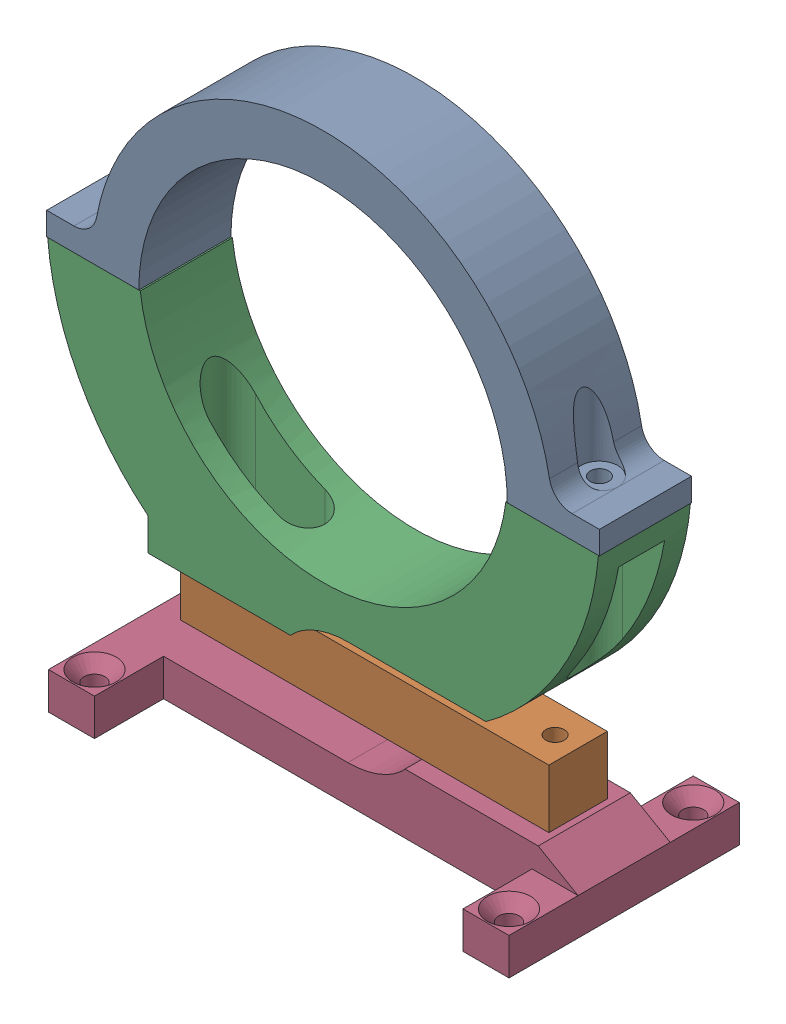
SolidWorks assembly Tank_holder, configuration Default. Lengths in mm.
Overall size (120 124.17 50).
4 component instances, 4 part files, 3 mates.
Components (placement in the parent):
- Top_Bracket-1: Top_Bracket [Default] at (618.8059 841.357 1270.3964) size (120 50 20)
- load_cell-1: load_cell [Default] at (624.1822 780.1955 1280.3964) size (80 12.7 12.7)
- Bottom_bracket-1: Bottom_bracket [Default] at (618.8059 846.357 1290.3964) x (1 0 0) z (0 0 -1) size (119.58 48.46 20)
- Base_bracket-1: Base_bracket [Default] at (624.1822 786.541 1270.3964) size (100 13 50)
Mates (geometry in assembly coordinates):
- Coincident1: coincident anti-aligned: circle of Top_Bracket-1; circle of Bottom_bracket-1
- Coincident2: coincident anti-aligned: circle of load_cell-1; circle of Bottom_bracket-1
- Concentric1: concentric aligned: circle of load_cell-1; circle of Base_bracket-1
